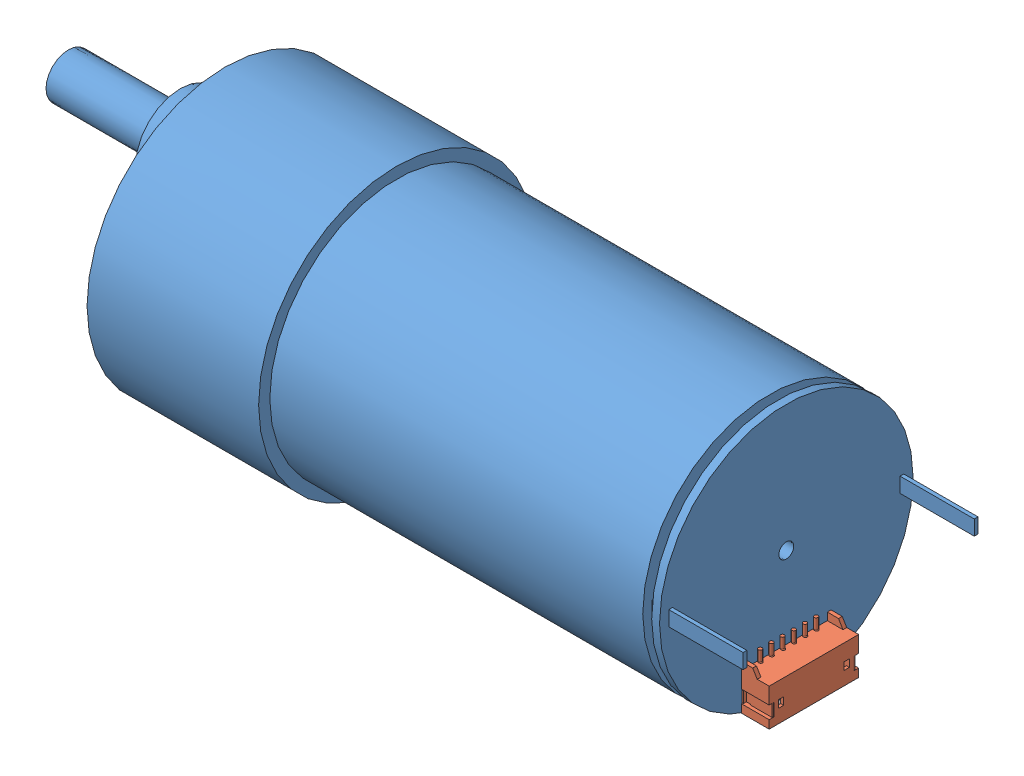
SolidWorks assembly CHR-GM37-545 (1-50), configuration Default. Lengths in mm.
Overall size (106.2 37 37).
2 component instances, 2 part files, 4 mates.
Components (placement in the parent):
- motor_CHR-GM37-3429K-ABHL-1: motor_CHR-GM37-3429K-ABHL [DC 12.0V 1000RMP-I10 without shaft] at origin size (106.2 37 37)
- S6B_ZR_SM4A_TF-1: S6B_ZR_SM4A_TF [Default] at (0 -3.106 0) x (1 0 0) z (0 0 -1) size (3.7 6.5 12)
Mates (geometry in assembly coordinates):
- 重合/共線/共點1: coincident anti-aligned: circle of motor_CHR-GM37-3429K-ABHL-1; plane of S6B_ZR_SM4A_TF-1 through (41.25 -9.906 -6) normal (-1 0 0)
- 平行1: parallel aligned: plane of motor_CHR-GM37-3429K-ABHL-1 through (51.2 -1 -15.75) normal (0 0 -1); plane of S6B_ZR_SM4A_TF-1 through (44.95 -15.906 -6) normal (0 0 -1)
- 重合/共線/共點2: coincident: point of motor_CHR-GM37-3429K-ABHL-1; point of S6B_ZR_SM4A_TF-1
- 重合/共線/共點3: coincident: circle of motor_CHR-GM37-3429K-ABHL-1; point of S6B_ZR_SM4A_TF-1
